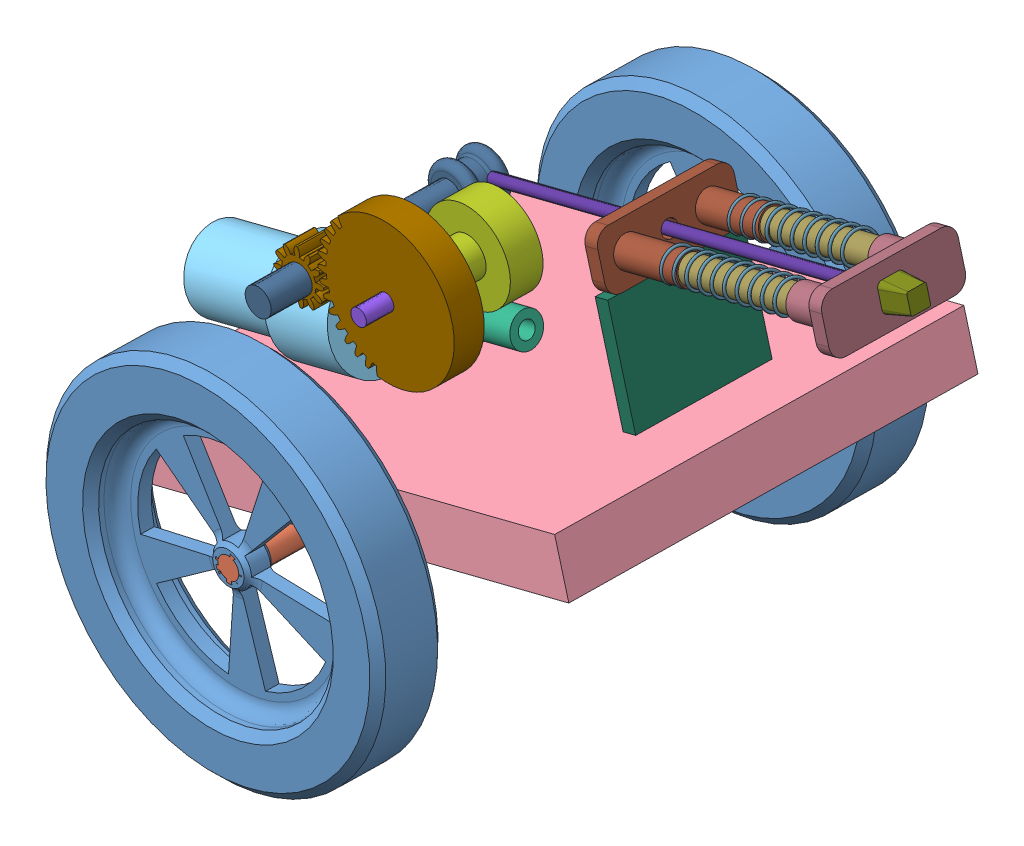
SolidWorks assembly hopbot, configuration Default. Lengths in mm.
Overall size (257.32 220.83 208.84).
25 component instances, 17 part files, 29 mates.
Components (placement in the parent):
- Wheel-1: Wheel [Default] at (153.0889 54.0501 242.6626) x (-0.591616 -0.806022 -0.017867) z (0.805928 -0.591853 0.013818) size (130 25 130)
- Wheel-2: Wheel [Default] at (156.9972 55.1705 62.7085) x (0.999531 -0.021713 0.021573) z (0.021573 0.999745 0.006693) size (130 25 130)
- axle-1: axle [Default] at (157.3772 55.2794 45.213) x (0.999697 0.011491 0.021783) z (-0.021713 -0.006224 0.999745) size (10 10 190)
- heavy duty external retaining ring_am-1: heavy duty external retaining ring_am [B27.8M - 3DM1-10] at (156.4001 54.9993 90.2015) x (-0.999426 0.026162 -0.021543) z (-0.021713 -0.006224 0.999745) size (12.01 13.7 0.9)
- heavy duty external retaining ring_am-2: heavy duty external retaining ring_am [B27.8M - 3DM1-10] at (154.2288 54.3769 190.176) x (0.933565 -0.357955 0.018047) z (0.021713 0.006224 -0.999745) size (12.01 13.7 0.9)
- base-1: base [Default] at (172.8306 85.6388 140.7619) x (-0.965028 -0.261173 -0.022585) z (0.261247 -0.965272 -0.000336) size (180 150 20.3)
- mech assss-2: mech assss [Default] at (19.8287 53.8894 183.2088) x (-0.021713 -0.006224 0.999745) z (0.965028 0.261173 0.022585) size (85 84.66 148.5)
  - motor 2-1: motor 2 [Default] at (-20.0328 -8.9413 64.9846) size (36.56 36.56 102.5)
  - worm gear part 1-1: worm gear part 1 [Default] at (-20.0328 -16.9313 156.9846) size (17.5 17.5 31)
  - worm gear part 2-1: worm gear part 2 [Default] at (-26.0328 -39.1813 177.2924) x (0 0 -1) z (1 0 0) size (32.5 32.5 20)
  - shaft between 2pi3 and wom-1: shaft between 2pi3 and wom [Default] at (-33.9558 -39.1813 177.2924) x (0 0.802001 0.597323) z (1 0 0) size (6 6 60)
  - gears 1 parts-1: gears 1 parts [Default] at (4.9895 -39.1813 177.2924) x (0 0 -1) z (1 0 0) size (81.08 72.3 27)
    - spur gear_am-2: spur gear_am [Metric - Spur gear 1.375M 36T 14.5PA 11FW ---S12O8H19L6N] x (0 0 1) z (0.834941 0.550339 0) size (19 52.19 52.19)
    - spur gear_am-3: spur gear_am [Metric - Spur gear 1.375M 12T 14.5PA 11FW ---S12B8H27L6N] at (34.6667 0 11) x (0 0 -1) z (0.092549 -0.995708 0) size (27 18.78 18.78)
  - pulley-2: pulley [Default] at (-47.5495 -31.8638 144.3817) x (-1 0 0) z (0 0.245825 -0.969314) size (85 19 19)
- assem3-1: assem3 [Default] at (243.7646 124.6731 228.6931) x (0.021713 0.006224 -0.999745) z (0.965028 0.261173 0.022585) size (50.03 20.07 94)
  - mount 1-1: mount 1 [Default] at (83.1556 34.1999 -20.6338) size (50 20 30)
  - mount 3-1: mount 3 [Default] at (74.1257 30.823 12.9837) x (0.99402 -0.109194 0) z (0 0 -1) size (9.6 9.6 49)
  - mount2-1: mount2 [Default] at (66.1694 39.939 73.3662) x (0.999999 -0.001471 0) z (0 0 -1) size (50 20 20)
  - spring-2: spring [Default] at (74.3292 31.0434 2.2218) x (0.374492 0.92723 0) z (0 0 1) size (13 13 51)
  - mount 3-2: mount 3 [Default] at (104.1257 30.823 12.9837) x (-0.689119 -0.724648 0) z (0 0 -1) size (9.6 9.6 49)
  - spring-3: spring [Default] at (104.4257 30.8209 -3.54) x (0.412087 0.911145 0) z (0 0 1) size (13 13 51)
- Part2-1: Part2 [Default] at (222.4251 130.961 143.5332) x (0.021713 0.006224 -0.999745) z (0.965028 0.261173 0.022585) size (50 40 5)
- Part3-1: Part3 [Default] at (308.2338 175.2683 137.3683) x (0.022097 0.004805 -0.999744) z (0.965028 0.261173 0.022585) size (10 10 10)
- Part4-1: Part4 [Default] at (154.6959 132.5307 137.6592) x (0.092862 -0.260011 -0.96113) z (0.965028 0.261173 0.022585) size (4 4 150)
Mates (geometry in assembly coordinates):
- Concentric1: concentric: cylinder of axle-1 through (153.2518 54.0968 235.1645) axis (0.021713 0.006224 -0.999745) radius 5; cylinder of heavy duty external retaining ring_am-2 through (154.2093 54.3713 191.0758) axis (0.021713 0.006224 -0.999745) radius 4.7
- Concentric2: concentric: cylinder of axle-1 through (153.2518 54.0968 235.1645) axis (0.021713 0.006224 -0.999745) radius 5; circle of heavy duty external retaining ring_am-1
- Concentric4: concentric: cylinder of Wheel-1 through (153.0889 54.0501 242.6626) axis (0.021713 0.006224 -0.999745) radius 4; cylinder of axle-1 through (153.2518 54.0968 235.1645) axis (0.021713 0.006224 -0.999745) radius 5
- Concentric5: concentric: cylinder of Wheel-2 through (156.9972 55.1705 62.7085) axis (0.021713 0.006224 -0.999745) radius 4; cylinder of axle-1 through (153.2518 54.0968 235.1645) axis (0.021713 0.006224 -0.999745) radius 5
- Coincident1: coincident: plane of Wheel-1 through (153.2518 54.0968 235.1645) normal (-0.021713 -0.006224 0.999745); plane of axle-1 through (153.2518 54.0968 235.1645) normal (-0.021713 -0.006224 0.999745)
- Coincident2: coincident: plane of Wheel-2 through (157.3772 55.2794 45.213) normal (0.021713 0.006224 -0.999745); plane of axle-1 through (157.3772 55.2794 45.213) normal (0.021713 0.006224 -0.999745)
- Distance1: distance = 35 mm: plane of heavy duty external retaining ring_am-2 through (154.2288 54.3769 190.176) normal (0.021713 0.006224 -0.999745); plane of Wheel-1 through (153.4689 54.159 225.1671) normal (0.021713 0.006224 -0.999745)
- Distance2: distance = 35 mm: plane of Wheel-2 through (157.16 55.2171 55.2104) normal (-0.021713 -0.006224 0.999745); plane of heavy duty external retaining ring_am-1 through (156.4001 54.9993 90.2015) normal (-0.021713 -0.006224 0.999745)
- Tangent1: tangent: cylinder of axle-1 through (153.2518 54.0968 235.1645) axis (0.021713 0.006224 -0.999745) radius 5; plane of base-1 through (178.1339 66.0438 140.755) normal (0.261247 -0.965272 -0.000336)
- Distance3: distance = 2.5 mm: plane of Wheel-2 through (156.9972 55.1705 62.7085) normal (-0.021713 -0.006224 0.999745); plane of base-1 through (266.6149 90.0161 67.8068) normal (0.021713 0.006224 -0.999745)
- Parallel2: parallel: plane of base-1 through (92.9099 43.005 63.7416) normal (-0.965028 -0.261173 -0.022585); plane of mech assss-2/motor 2-1 through (80.6397 79.6171 164.6518) normal (-0.965028 -0.261173 -0.022585)
- Tangent4: tangent: cylinder of Wheel-2 through (157.54 55.3261 37.7149) axis (-0.021713 -0.006224 0.999745) radius 65; plane of base-1 through (92.9099 43.005 63.7416) normal (-0.965028 -0.261173 -0.022585)
- Coincident8: coincident: plane of base-1 through (92.9099 43.005 63.7416) normal (-0.965028 -0.261173 -0.022585); plane of mech assss-2/motor 2-1 through (80.6397 79.6171 164.6518) normal (-0.965028 -0.261173 -0.022585)
- Tangent5: tangent: plane of base-1 through (172.8306 85.6388 140.7619) normal (-0.261247 0.965272 0.000336); cylinder of mech assss-2/motor 2-1 through (140.4714 95.8098 166.052) axis (-0.965028 -0.261173 -0.022585) radius 18.28
- Parallel3: parallel: line of base-1 through (261.3116 109.6111 67.8136) axis (-0.021713 -0.006224 0.999745); cylinder of mech assss-2/shaft between 2pi3 and wom-1 through (180.1193 137.8518 213.2636) axis (0.021713 0.006224 -0.999745) radius 3
- Distance5: distance = 8 mm: line of assembly; plane of mech assss-2/pulley-2 through (152.0082 122.691 132.5383) normal (0.021713 0.006224 -0.999745)
- Parallel4: parallel: plane of base-1 through (266.6149 90.0161 67.8068) normal (0.965028 0.261173 0.022585); plane of assem3-1/mount2-1 through (305.6112 182.8106 162.2115) normal (0.965028 0.261173 0.022585)
- Parallel5: parallel: plane of base-1 through (172.8306 85.6388 140.7619) normal (-0.261247 0.965272 0.000336); plane of assem3-1/mount 1-1 through (224.7819 141.1325 157.2395) normal (0.261247 -0.965272 -0.000336)
- Distance6: distance = 40 mm: plane of assem3-1/mount 1-1 through (224.7385 141.1201 159.239) normal (0.261247 -0.965272 -0.000336); plane of base-1 through (172.8306 85.6388 140.7619) normal (-0.261247 0.965272 0.000336)
- Distance7: distance = 20 mm: plane of mech assss-2/pulley-2 through (152.0082 122.691 132.5383) normal (0.021713 0.006224 -0.999745); plane of assem3-1/mount 1-1 through (221.7968 155.8792 114.2555) normal (0.021713 0.006224 -0.999745)
- Coincident17: coincident: plane of base-1 through (266.6149 90.0161 67.8068) normal (0.965028 0.261173 0.022585); circle of assem3-1/mount 1-1
- Parallel7: parallel: line of base-1 through (261.3116 109.6111 67.8136) axis (-0.021713 -0.006224 0.999745); line of Part2-1 through (230.0661 101.1219 162.1064) axis (0.021713 0.006224 -0.999745)
- Coincident22: coincident: plane of assem3-1/mount 1-1 through (224.7819 141.1325 157.2395) normal (0.261247 -0.965272 -0.000336); plane of Part2-1 through (224.4413 141.0386 162.2328) normal (-0.261247 0.965272 0.000336)
- Coincident23: coincident: plane of assem3-1/mount 1-1 through (221.8402 155.8917 112.256) normal (0.021713 0.006224 -0.999745); plane of Part2-1 through (225.527 141.3498 112.2455) normal (0.021713 0.006224 -0.999745)
- Coincident24: coincident: plane of assem3-1/mount2-1 through (305.6112 182.8106 162.2115) normal (0.965028 0.261173 0.022585); plane of Part3-1 through (308.2772 175.2808 135.3688) normal (-0.965028 -0.261173 -0.022585)
- Distance9: distance = 5 mm: line of assem3-1/mount2-1 through (305.3873 183.7345 161.0939) axis (0.022097 0.004805 -0.999744); line of Part3-1 through (307.0656 178.9891 144.2595) axis (0.022097 0.004805 -0.999744)
- Distance10: distance = 20 mm: line of Part3-1 through (307.7627 177.1053 136.2553) axis (0.261214 -0.96528 0.001134); line of assem3-1/mount2-1 through (310.2966 169.4708 116.2695) axis (-0.261214 0.96528 -0.001134)
- Tangent6: tangent: cylinder of mech assss-2/pulley-2 through (148.6755 128.82 127.8735) axis (0.021713 0.006224 -0.999745) radius 7; plane of Part4-1 through (154.7394 132.5431 135.6597) normal (-0.965028 -0.261173 -0.022585)
- Concentric6: concentric: cylinder of assem3-1/mount 1-1 through (222.6037 150.9097 137.2479) axis (-0.965028 -0.261173 -0.022585) radius 3; cylinder of Part4-1 through (299.4935 171.719 139.0474) axis (-0.965028 -0.261173 -0.022585) radius 2
